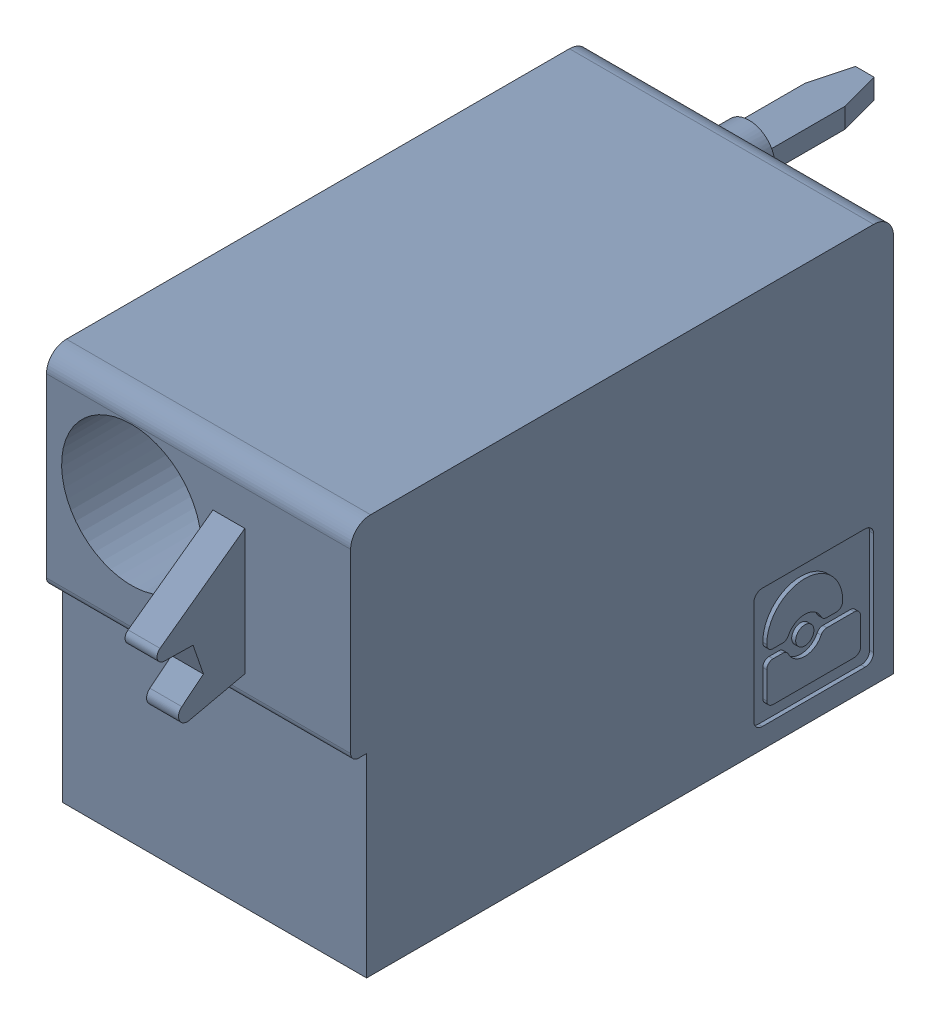
SolidWorks assembly J75, configuration Default. Lengths in mm.
Overall size (7.62 10 19.2).
2 component instances, 1 part files, 0 mates.
Components (placement in the parent):
- 1790487-1: 1790487 [Default] at (211.225 -5.67 -10.6) x (0 1 0) z (1 0 0) size (10 19.2 7.62)
  - ffkdsa1-v2-7.62-1: ffkdsa1-v2-7.62 [Default] at (-15.6914 -27.508 9.12) x (0 -1 0) z (0 0 1) size (19.2 10 7.62)
